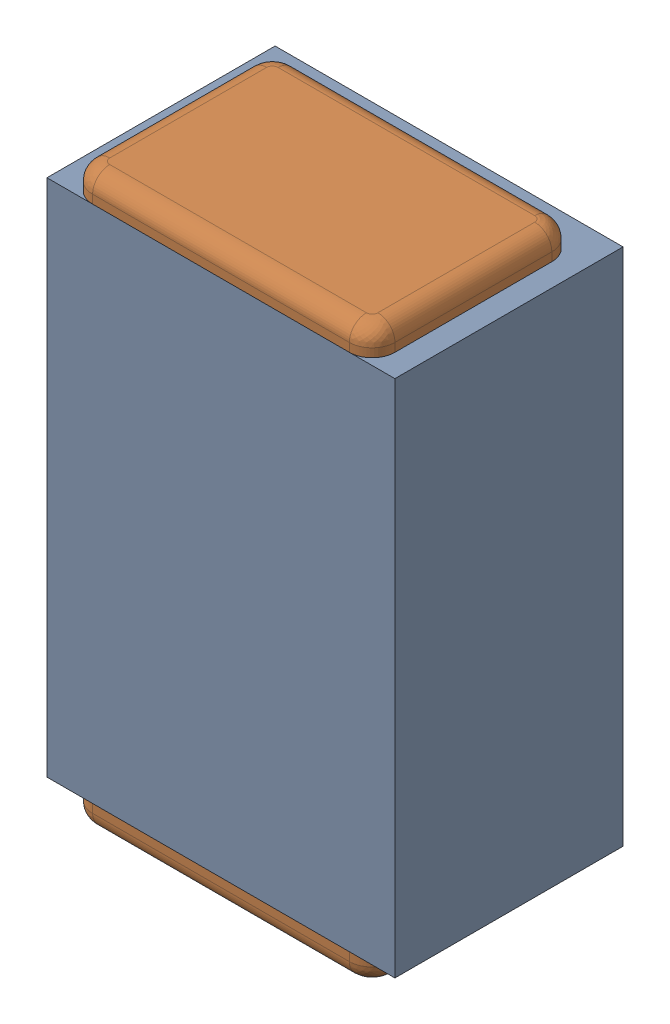
SolidWorks assembly C31, configuration Default. Lengths in mm.
Overall size (0.61 1 0.4).
3 component instances, 2 part files, 0 mates.
Components (placement in the parent):
- 1088881848-1: 1088881848 [Default] at (9.975 31.775 -2.044) size (0.61 0.91 0.4)
  - Extruded-1-1: Extruded-1 [Default] at origin size (0.61 0.91 0.4)
- C0402-1: C0402 [Default] at (9.9751 31.7751 -1.644) x (0 1 0) z (-1 0 0) size (1 0.36 0.54)
